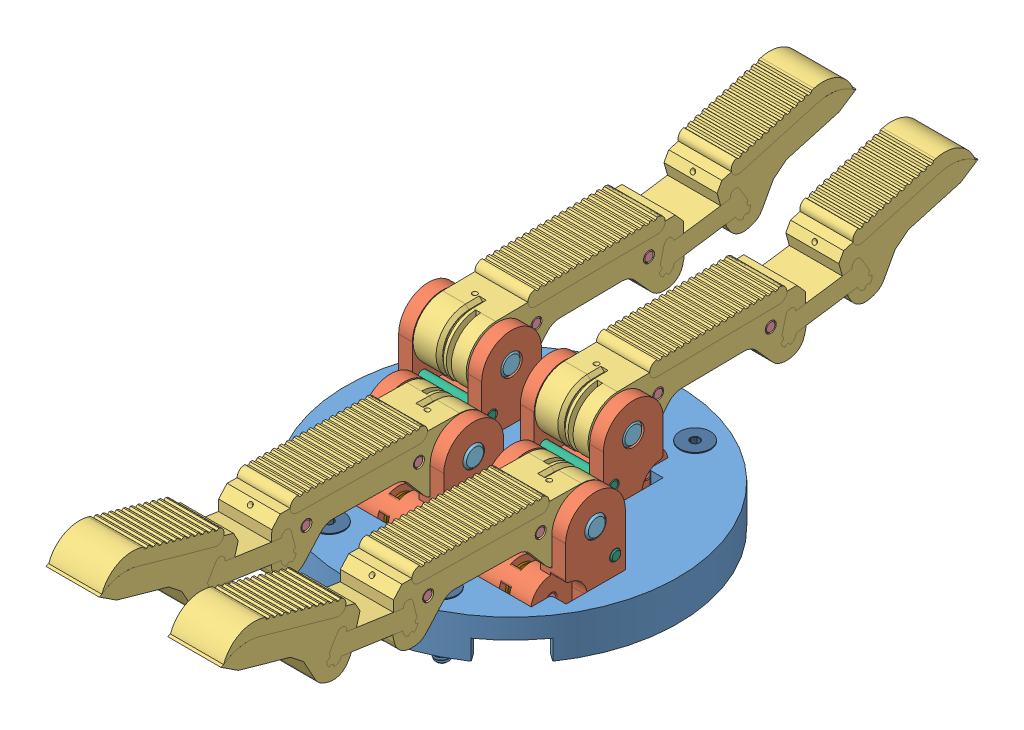
SolidWorks assembly block_top_pf_t, configuration Default. Lengths in mm.
Overall size (100 57.13 247.1).
49 component instances, 10 part files, 20 mates.
Components (placement in the parent):
- a1_p_t-1: a1_p_t [Default] at origin size (100 12 100)
- block_finger_pf_t-1: block_finger_pf_t [Default] at (9.2417 -4.5 0) size (25.4 45.69 121.76)
  - c1_t-1: c1_t [Default] at origin size (25 30.67 32)
  - finger_pf_t-1: finger_pf_t [Default] at (-0.15 21.67 -14.7858) x (1 0 0) z (0 -0.013363 0.999911) size (16 29.93 117.65)
  - 98381A472 D1-8 L5-8-1: 98381A472 D1-8 L5-8 [98381A472] at (-0.0875 23.995 -26.9308) size (15.88 3.17 3.17)
  - 98381A472 D1-8 L5-8-2: 98381A472 D1-8 L5-8 [98381A472] at (-0.0875 24.448 -60.8289) size (15.88 3.17 3.17)
  - 98381A542 D1-4 L1-1: 98381A542 D1-4 L1 [98381A542] at (-0.2 21.67 -14.7858) size (25.4 6.35 6.35)
  - 98381A475 D1-8 L1-1: 98381A475 D1-8 L1 [98381A475] at (-0.2 11.2575 -8.8732) size (25.4 3.17 3.17)
  - 98381A472 D1-8 L5-8-3: 98381A472 D1-8 L5-8 [98381A472] at (0.0625 4.925 -23.535) size (15.88 3.17 3.17)
  - 93365A120 4-40 insert-1: 93365A120 4-40 insert [93365A120] at (-0.15 27.5639 -100.2943) x (1 0 0) z (0 0.622567 -0.782567) size (4.37 3.82 4.37)
  - 91253A106 4-40 L1-4 countersunk-1: 91253A106 4-40 L1-4 countersunk [91253A106] at (-0.15 25.9039 -101.6148) x (1 0 0) z (0 -0.782567 -0.622567) size (6.48 6.48 6.63)
  - 3434T31 - nylon pulley-1: 3434T31 - nylon pulley [Default] at (-0.15 4.925 -23.535) x (0 -0.840446 -0.541896) z (0 -0.541896 0.840446) size (9.5 2.4 9.5)
- block_finger_pf_t-2: block_finger_pf_t [Default] at (-27.425 -4.5 0.0007) size (25.4 45.69 121.76)
  - c1_t-1: c1_t [Default] at origin size (25 30.67 32)
  - finger_pf_t-1: finger_pf_t [Default] at (-0.15 21.67 -14.7858) x (1 0 0) z (0 -0.013363 0.999911) size (16 29.93 117.65)
  - 98381A472 D1-8 L5-8-1: 98381A472 D1-8 L5-8 [98381A472] at (-0.0875 23.995 -26.9308) size (15.88 3.17 3.17)
  - 98381A472 D1-8 L5-8-2: 98381A472 D1-8 L5-8 [98381A472] at (-0.0875 24.448 -60.8289) size (15.88 3.17 3.17)
  - 98381A542 D1-4 L1-1: 98381A542 D1-4 L1 [98381A542] at (-0.2 21.67 -14.7858) size (25.4 6.35 6.35)
  - 98381A475 D1-8 L1-1: 98381A475 D1-8 L1 [98381A475] at (-0.2 11.2575 -8.8732) size (25.4 3.17 3.17)
  - 98381A472 D1-8 L5-8-3: 98381A472 D1-8 L5-8 [98381A472] at (0.0625 4.925 -23.535) size (15.88 3.17 3.17)
  - 93365A120 4-40 insert-1: 93365A120 4-40 insert [93365A120] at (-0.15 27.5639 -100.2943) x (1 0 0) z (0 0.622567 -0.782567) size (4.37 3.82 4.37)
  - 91253A106 4-40 L1-4 countersunk-1: 91253A106 4-40 L1-4 countersunk [91253A106] at (-0.15 25.9039 -101.6148) x (1 0 0) z (0 -0.782567 -0.622567) size (6.48 6.48 6.63)
  - 3434T31 - nylon pulley-1: 3434T31 - nylon pulley [Default] at (-0.15 4.925 -23.535) x (0 -0.840446 -0.541896) z (0 -0.541896 0.840446) size (9.5 2.4 9.5)
- block_finger_pf_t-3: block_finger_pf_t [Default] at (-9.2417 -4.5 0) x (-1 0 0) z (0 0 -1) size (25.4 45.69 121.76)
  - c1_t-1: c1_t [Default] at origin size (25 30.67 32)
  - finger_pf_t-1: finger_pf_t [Default] at (-0.15 21.67 -14.7858) x (1 0 0) z (0 -0.013363 0.999911) size (16 29.93 117.65)
  - 98381A472 D1-8 L5-8-1: 98381A472 D1-8 L5-8 [98381A472] at (-0.0875 23.995 -26.9308) size (15.88 3.17 3.17)
  - 98381A472 D1-8 L5-8-2: 98381A472 D1-8 L5-8 [98381A472] at (-0.0875 24.448 -60.8289) size (15.88 3.17 3.17)
  - 98381A542 D1-4 L1-1: 98381A542 D1-4 L1 [98381A542] at (-0.2 21.67 -14.7858) size (25.4 6.35 6.35)
  - 98381A475 D1-8 L1-1: 98381A475 D1-8 L1 [98381A475] at (-0.2 11.2575 -8.8732) size (25.4 3.17 3.17)
  - 98381A472 D1-8 L5-8-3: 98381A472 D1-8 L5-8 [98381A472] at (0.0625 4.925 -23.535) size (15.88 3.17 3.17)
  - 93365A120 4-40 insert-1: 93365A120 4-40 insert [93365A120] at (-0.15 27.5639 -100.2943) x (1 0 0) z (0 0.622567 -0.782567) size (4.37 3.82 4.37)
  - 91253A106 4-40 L1-4 countersunk-1: 91253A106 4-40 L1-4 countersunk [91253A106] at (-0.15 25.9039 -101.6148) x (1 0 0) z (0 -0.782567 -0.622567) size (6.48 6.48 6.63)
  - 3434T31 - nylon pulley-1: 3434T31 - nylon pulley [Default] at (-0.15 4.925 -23.535) x (0 -0.840446 -0.541896) z (0 -0.541896 0.840446) size (9.5 2.4 9.5)
- block_finger_pf_t-4: block_finger_pf_t [Default] at (27.425 -4.5 0) x (-1 0 0) z (0 0 -1) size (25.4 45.69 121.76)
  - c1_t-1: c1_t [Default] at origin size (25 30.67 32)
  - finger_pf_t-1: finger_pf_t [Default] at (-0.15 21.67 -14.7858) x (1 0 0) z (0 -0.013363 0.999911) size (16 29.93 117.65)
  - 98381A472 D1-8 L5-8-1: 98381A472 D1-8 L5-8 [98381A472] at (-0.0875 23.995 -26.9308) size (15.88 3.17 3.17)
  - 98381A472 D1-8 L5-8-2: 98381A472 D1-8 L5-8 [98381A472] at (-0.0875 24.448 -60.8289) size (15.88 3.17 3.17)
  - 98381A542 D1-4 L1-1: 98381A542 D1-4 L1 [98381A542] at (-0.2 21.67 -14.7858) size (25.4 6.35 6.35)
  - 98381A475 D1-8 L1-1: 98381A475 D1-8 L1 [98381A475] at (-0.2 11.2575 -8.8732) size (25.4 3.17 3.17)
  - 98381A472 D1-8 L5-8-3: 98381A472 D1-8 L5-8 [98381A472] at (0.0625 4.925 -23.535) size (15.88 3.17 3.17)
  - 93365A120 4-40 insert-1: 93365A120 4-40 insert [93365A120] at (-0.15 27.5639 -100.2943) x (1 0 0) z (0 0.622567 -0.782567) size (4.37 3.82 4.37)
  - 91253A106 4-40 L1-4 countersunk-1: 91253A106 4-40 L1-4 countersunk [91253A106] at (-0.15 25.9039 -101.6148) x (1 0 0) z (0 -0.782567 -0.622567) size (6.48 6.48 6.63)
  - 3434T31 - nylon pulley-1: 3434T31 - nylon pulley [Default] at (-0.15 4.925 -23.535) x (0 -0.840446 -0.541896) z (0 -0.541896 0.840446) size (9.5 2.4 9.5)
- 92210A197 8-32 L3-4 countersunk-1: 92210A197 8-32 L3-4 countersunk [92210A197] at (17.0093 1.7845 38.128) x (0.445326 0 -0.895368) z (0 1 0) size (9.12 9.12 19.5)
- 92210A197 8-32 L3-4 countersunk-2: 92210A197 8-32 L3-4 countersunk [92210A197] at (-17.0093 1.7845 38.128) x (1 0 0) z (0 1 0) size (9.12 9.12 19.5)
- 92210A197 8-32 L3-4 countersunk-3: 92210A197 8-32 L3-4 countersunk [92210A197] at (17.0093 1.7845 -38.128) x (0.865412 0 0.501062) z (0 1 0) size (9.12 9.12 19.5)
- 92210A197 8-32 L3-4 countersunk-4: 92210A197 8-32 L3-4 countersunk [92210A197] at (-17.0093 1.7845 -38.128) x (1 0 0) z (0 1 0) size (9.12 9.12 19.5)
Mates (geometry in assembly coordinates):
- Coincident1: coincident anti-aligned: plane of a1_p_t-1 through (-14.925 1.5 -5.7858) normal (-1 0 0); plane of block_finger_pf_t-2/c1_t-1 through (-14.925 17.17 -14.785) normal (1 0 0)
- Coincident2: coincident anti-aligned: plane of a1_p_t-1 through (-19.425 1.5 -29.7843) normal (0 0 1); plane of block_finger_pf_t-2/c1_t-1 through (-14.925 0.425 -29.7843) normal (0 0 -1)
- Coincident3: coincident anti-aligned: plane of a1_p_t-1 through (0 -1.5 0) normal (0 -1 0); plane of block_finger_pf_t-2/c1_t-1 through (-39.925 -1.5 -5.785) normal (0 1 0)
- Coincident4: coincident anti-aligned: plane of a1_p_t-1 through (21.7417 1.5 -5.7858) normal (-1 0 0); plane of block_finger_pf_t-1/c1_t-1 through (21.7417 17.17 -14.7858) normal (1 0 0)
- Coincident5: coincident anti-aligned: plane of a1_p_t-1 through (-3.4083 1.5 -5.7858) normal (0 0 -1); plane of block_finger_pf_t-1/c1_t-1 through (-3.2583 17.17 -5.7858) normal (0 0 1)
- Coincident6: coincident anti-aligned: plane of a1_p_t-1 through (0 -1.5 0) normal (0 -1 0); plane of block_finger_pf_t-1/c1_t-1 through (-3.2583 -1.5 -5.7858) normal (0 1 0)
- Coincident7: coincident anti-aligned: plane of a1_p_t-1 through (14.925 1.5 5.7858) normal (1 0 0); plane of block_finger_pf_t-4/c1_t-1 through (14.925 17.17 14.7858) normal (-1 0 0)
- Coincident8: coincident anti-aligned: plane of a1_p_t-1 through (40.075 1.5 5.7858) normal (0 0 1); plane of block_finger_pf_t-4/c1_t-1 through (39.925 17.17 5.7858) normal (0 0 -1)
- Coincident9: coincident anti-aligned: plane of a1_p_t-1 through (0 -1.5 0) normal (0 -1 0); plane of block_finger_pf_t-4/c1_t-1 through (39.925 -1.5 33.785) normal (0 1 0)
- Coincident10: coincident anti-aligned: plane of a1_p_t-1 through (-21.7417 1.5 23.7858) normal (1 0 0); plane of block_finger_pf_t-3/c1_t-1 through (-21.7417 17.17 14.7858) normal (-1 0 0)
- Coincident11: coincident anti-aligned: plane of a1_p_t-1 through (-21.7417 1.5 5.7858) normal (0 0 1); plane of block_finger_pf_t-3/c1_t-1 through (3.2583 17.17 5.7858) normal (0 0 -1)
- Coincident12: coincident anti-aligned: plane of a1_p_t-1 through (0 -1.5 0) normal (0 -1 0); plane of block_finger_pf_t-3/c1_t-1 through (3.2583 -1.5 5.7858) normal (0 1 0)
- Concentric1: concentric aligned: cylinder of a1_p_t-1 through (17.0093 1.5 38.128) axis (0 1 0) radius 2.4574; circle of 92210A197 8-32 L3-4 countersunk-1
- Coincident13: coincident aligned: cone of a1_p_t-1 through (17.0093 1.5 38.128) axis (0 -1 0); cone of 92210A197 8-32 L3-4 countersunk-1 through (17.0093 -1.0603 38.128) axis (0 -1 0)
- Concentric3: concentric aligned: cylinder of a1_p_t-1 through (17.0093 1.5 -38.128) axis (0 1 0) radius 2.4574; circle of 92210A197 8-32 L3-4 countersunk-3
- Coincident14: coincident aligned: cone of a1_p_t-1 through (17.0093 1.5 -38.128) axis (0 -1 0); cone of 92210A197 8-32 L3-4 countersunk-3 through (17.0093 -1.0603 -38.128) axis (0 -1 0)
- Concentric5: concentric aligned: cylinder of a1_p_t-1 through (-17.0093 1.5 -38.128) axis (0 1 0) radius 2.4574; circle of 92210A197 8-32 L3-4 countersunk-4
- Coincident15: coincident aligned: cone of a1_p_t-1 through (-17.0093 1.5 -38.128) axis (0 -1 0); cone of 92210A197 8-32 L3-4 countersunk-4 through (-17.0093 -1.0603 -38.128) axis (0 -1 0)
- Concentric7: concentric aligned: cylinder of a1_p_t-1 through (-17.0093 1.5 38.128) axis (0 1 0) radius 2.4574; circle of 92210A197 8-32 L3-4 countersunk-2
- Coincident16: coincident aligned: cone of a1_p_t-1 through (-17.0093 1.5 38.128) axis (0 -1 0); cone of 92210A197 8-32 L3-4 countersunk-2 through (-17.0093 -1.0603 38.128) axis (0 -1 0)
